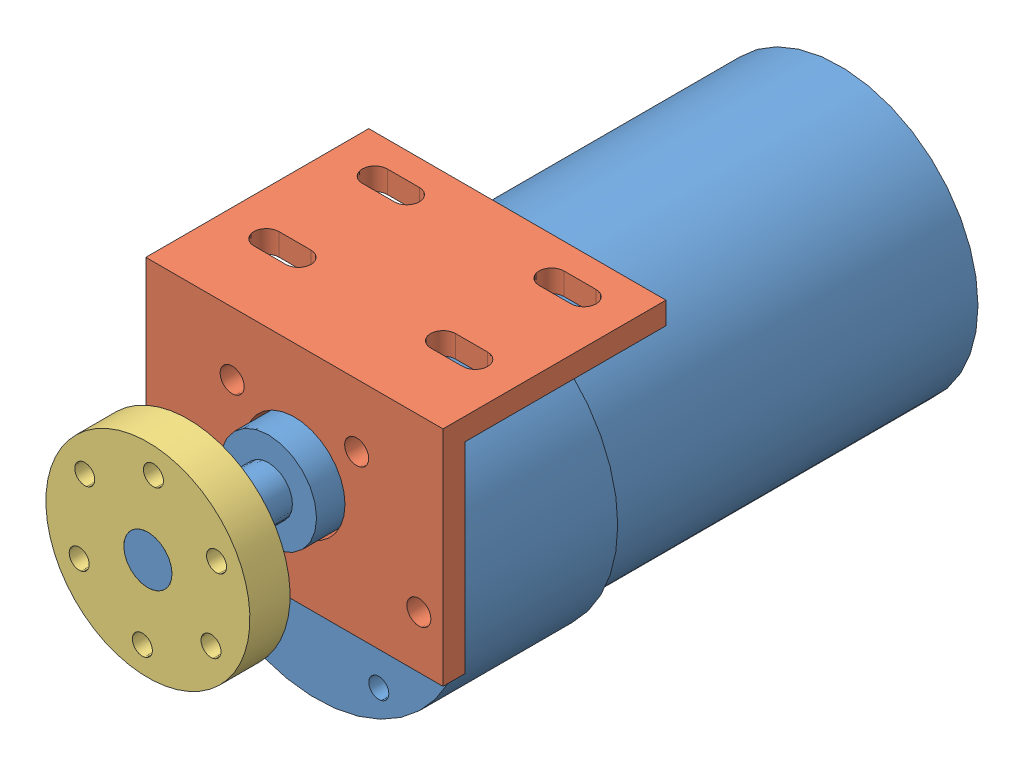
SolidWorks assembly Motor Assembly, configuration Default. Lengths in mm.
Overall size (37 39.76 86.1).
3 component instances, 3 part files, 7 mates.
Components (placement in the parent):
- motor-1: motor [Default] at (29.0457 45.957 89.0748) size (37 37 86.1)
- motor mount-1: motor mount [Default] at (29.0457 67.217 91.8348) x (-1 0 0) z (0 0 1) size (37 27.76 27.76)
- mounting hub-1: mounting hub [Default] at (29.0457 52.957 110.0748) x (-0.072656 -0.997357 0) z (0 0 1) size (25.4 25.4 9.2)
Mates (geometry in assembly coordinates):
- Concentric1: concentric anti-aligned: circle of motor-1; cylinder of motor mount-1 through (29.0457 52.957 91.8348) axis (0 0 -1) radius 6.3
- Concentric2: concentric anti-aligned: cylinder of motor-1 through (21.2957 59.3804 89.0748) axis (0 0 1) radius 1.25; cylinder of motor mount-1 through (21.2957 59.3804 89.0748) axis (0 0 -1) radius 1.5
- Coincident1: coincident anti-aligned: plane of motor-1 through (29.0457 45.957 89.0748) normal (0 0 1); plane of motor mount-1 through (10.5457 64.457 89.0748) normal (0 0 -1)
- Coincident2: coincident aligned: circle of motor-1; circle of mounting hub-1
- Concentric3: concentric aligned: circle of motor-1; cylinder of Wheel-1 through (29.0457 52.957 223.463) axis (0 0 1) radius 6.5
- Concentric4: concentric aligned: cylinder of mounting hub-1 through (37.5963 57.0966 110.0748) axis (0 0 1) radius 1.25; cylinder of Wheel-1 through (37.5963 57.0966 112.5748) axis (0 0 1) radius 1.25
- Coincident3: coincident anti-aligned: plane of mounting hub-1 through (32.0377 52.739 110.0748) normal (0 0 1); plane of Wheel-1 through (29.0457 52.957 110.0748) normal (0 0 -1)
